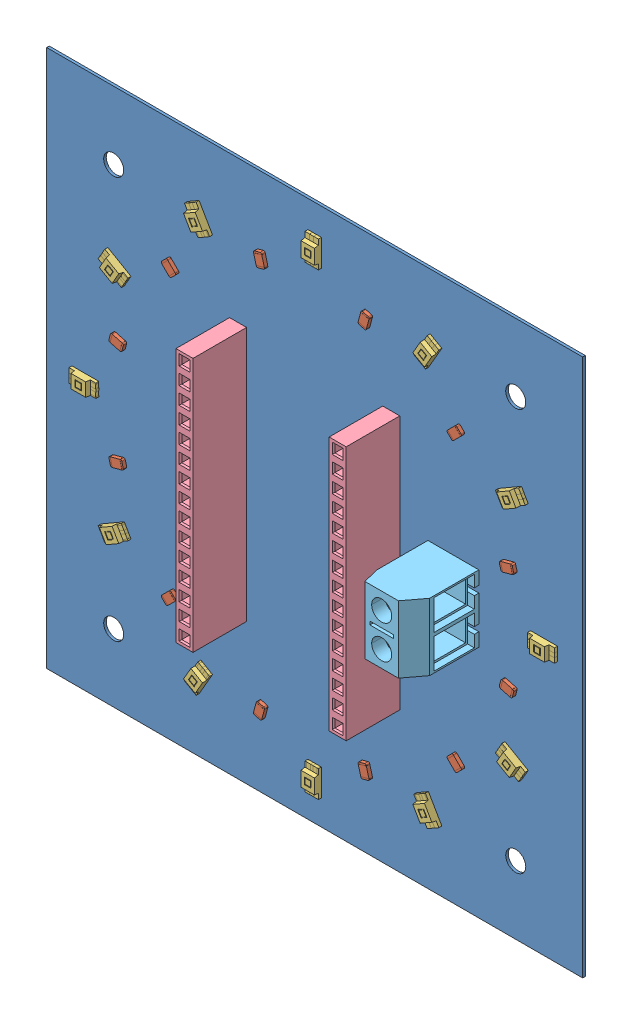
SolidWorks assembly CircularLightSensor, configuration Valor predeterminado. Lengths in mm.
Overall size (80 80.26 14).
28 component instances, 5 part files, 0 mates.
Components (placement in the parent):
- BoardOutline_CircularLightSensor-1: BoardOutline_CircularLightSensor [Valor predeterminado] at origin size (80 80.26 0.39)
- Resistor_SMD_0805_Resistor_SMD_0805-1: Resistor_SMD_0805_Resistor_SMD_0805 [Valor predeterminado] at (18.6737 61.3263 0.3912) x (0.707107 -0.707107 0) z (0 0 1) size (2 1.27 0.51)
- Resistor_SMD_0805_Resistor_SMD_0805-2: Resistor_SMD_0805_Resistor_SMD_0805 [Valor predeterminado] at (32.194 10.8677 0.3912) x (0.258819 0.965926 0) z (0 0 1) size (2 1.27 0.51)
- Resistor_SMD_0805_Resistor_SMD_0805-3: Resistor_SMD_0805_Resistor_SMD_0805 [Valor predeterminado] at (69.1323 47.806 0.3912) x (-0.965926 -0.258819 0) z (0 0 1) size (2 1.27 0.51)
- Resistor_SMD_0805_Resistor_SMD_0805-4: Resistor_SMD_0805_Resistor_SMD_0805 [Valor predeterminado] at (10.8677 47.806 0.3912) x (0.965926 -0.258819 0) z (0 0 1) size (2 1.27 0.51)
- Resistor_SMD_0805_Resistor_SMD_0805-5: Resistor_SMD_0805_Resistor_SMD_0805 [Valor predeterminado] at (47.806 10.8677 0.3912) x (-0.258819 0.965926 0) z (0 0 1) size (2 1.27 0.51)
- Resistor_SMD_0805_Resistor_SMD_0805-6: Resistor_SMD_0805_Resistor_SMD_0805 [Valor predeterminado] at (61.3263 61.3263 0.3912) x (-0.707107 -0.707107 0) z (0 0 1) size (2 1.27 0.51)
- Resistor_SMD_0805_Resistor_SMD_0805-7: Resistor_SMD_0805_Resistor_SMD_0805 [Valor predeterminado] at (10.8677 32.194 0.3912) x (0.965926 0.258819 0) z (0 0 1) size (2 1.27 0.51)
- Resistor_SMD_0805_Resistor_SMD_0805-8: Resistor_SMD_0805_Resistor_SMD_0805 [Valor predeterminado] at (61.3263 18.6737 0.3912) x (-0.707107 0.707107 0) z (0 0 1) size (2 1.27 0.51)
- Resistor_SMD_0805_Resistor_SMD_0805-9: Resistor_SMD_0805_Resistor_SMD_0805 [Valor predeterminado] at (47.806 69.1323 0.3912) x (-0.258819 -0.965926 0) z (0 0 1) size (2 1.27 0.51)
- Resistor_SMD_0805_Resistor_SMD_0805-10: Resistor_SMD_0805_Resistor_SMD_0805 [Valor predeterminado] at (18.6737 18.6737 0.3912) x (0.707107 0.707107 0) z (0 0 1) size (2 1.27 0.51)
- Resistor_SMD_0805_Resistor_SMD_0805-11: Resistor_SMD_0805_Resistor_SMD_0805 [Valor predeterminado] at (69.1323 32.194 0.3912) x (-0.965926 0.258819 0) z (0 0 1) size (2 1.27 0.51)
- Resistor_SMD_0805_Resistor_SMD_0805-12: Resistor_SMD_0805_Resistor_SMD_0805 [Valor predeterminado] at (32.194 69.1323 0.3912) x (0.258819 -0.965926 0) z (0 0 1) size (2 1.27 0.51)
- TEMT6000_TEMT6000-1: TEMT6000_TEMT6000 [Valor predeterminado] at (22.888 69.6389 0.3912) x (-0.5 0.866025 0) z (0 0 1) size (4 2 1.05)
- TEMT6000_TEMT6000-2: TEMT6000_TEMT6000 [Valor predeterminado] at (22.888 10.3612 0.3912) x (-0.5 -0.866025 0) z (0 0 1) size (4 2 1.05)
- TEMT6000_TEMT6000-3: TEMT6000_TEMT6000 [Valor predeterminado] at (74.224 40 0.3912) size (4 2 1.05)
- TEMT6000_TEMT6000-4: TEMT6000_TEMT6000 [Valor predeterminado] at (10.3612 57.112 0.3912) x (-0.866025 0.5 0) z (0 0 1) size (4 2 1.05)
- TEMT6000_TEMT6000-5: TEMT6000_TEMT6000 [Valor predeterminado] at (40 5.776 0.3912) x (0 -1 0) z (0 0 1) size (4 2 1.05)
- TEMT6000_TEMT6000-6: TEMT6000_TEMT6000 [Valor predeterminado] at (69.6389 57.112 0.3912) x (0.866025 0.5 0) z (0 0 1) size (4 2 1.05)
- TEMT6000_TEMT6000-7: TEMT6000_TEMT6000 [Valor predeterminado] at (5.776 40 0.3912) x (-1 0 0) z (0 0 1) size (4 2 1.05)
- TEMT6000_TEMT6000-8: TEMT6000_TEMT6000 [Valor predeterminado] at (57.112 10.3612 0.3912) x (0.5 -0.866025 0) z (0 0 1) size (4 2 1.05)
- TEMT6000_TEMT6000-9: TEMT6000_TEMT6000 [Valor predeterminado] at (57.112 69.6389 0.3912) x (0.5 0.866025 0) z (0 0 1) size (4 2 1.05)
- TEMT6000_TEMT6000-10: TEMT6000_TEMT6000 [Valor predeterminado] at (10.3612 22.888 0.3912) x (-0.866025 -0.5 0) z (0 0 1) size (4 2 1.05)
- TEMT6000_TEMT6000-11: TEMT6000_TEMT6000 [Valor predeterminado] at (69.6389 22.888 0.3912) x (0.866025 -0.5 0) z (0 0 1) size (4 2 1.05)
- TEMT6000_TEMT6000-12: TEMT6000_TEMT6000 [Valor predeterminado] at (40 74.224 0.3912) x (0 1 0) z (0 0 1) size (4 2 1.05)
- Pitch_female_15_pins_Pitch_15_pins_F-1: Pitch_female_15_pins_Pitch_15_pins_F [Valor predeterminado] at (51.43 40 0.3912) x (0 1 0) z (0 0 1) size (38 2.54 12)
- Pitch_female_15_pins_Pitch_15_pins_F-2: Pitch_female_15_pins_Pitch_15_pins_F [Valor predeterminado] at (28.57 40 0.3912) x (0 1 0) z (0 0 1) size (38 2.54 12)
- Kf301_2_PINS_KF301_2_pins-1: Kf301_2_PINS_KF301_2_pins [Valor predeterminado] at (60 40 0.3912) x (0 1 0) z (0 0 1) size (10 7.6 14)
